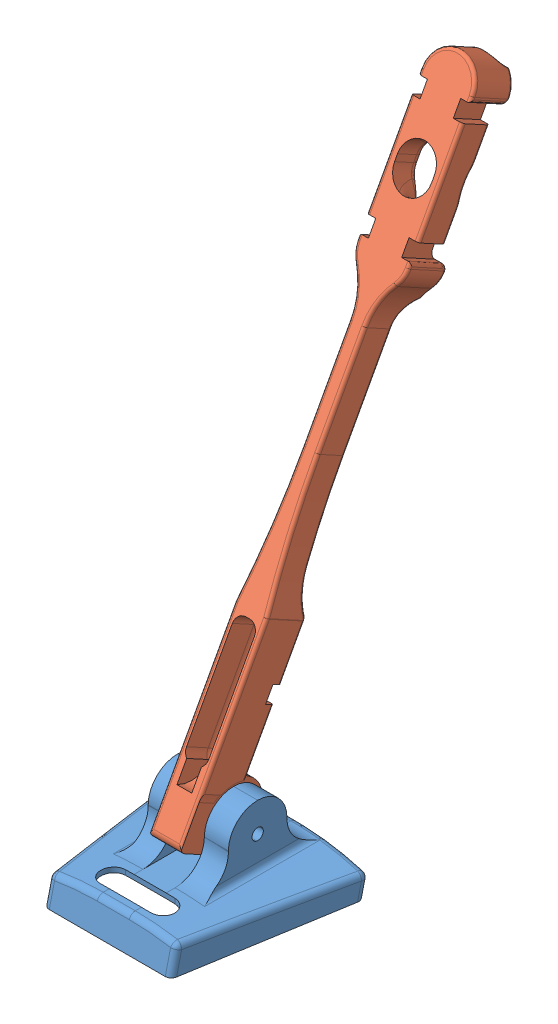
SolidWorks assembly Assem1, configuration Default. Lengths in mm.
Overall size (29.13 103.19 67.79).
2 component instances, 2 part files, 3 mates.
Components (placement in the parent):
- ant mount2-1: ant mount2 [Default] x (1 0 0) z (0 0.23129 0.972885) size (29.13 18.24 26.5)
- ant mount1-1: ant mount1 [Default] at (0 83.6021 -43.0844) x (1 0 0) z (0 0.478551 0.878059) size (8.4 100 12.28)
Mates (geometry in assembly coordinates):
- Width1: width anti-aligned: plane of ant mount2-1 through (-2.6 3.0626 -9.75) normal (1 0 0); plane of ant mount1-1 through (2.6 3.0626 -9.75) normal (-1 0 0); plane of ant mount2-1 through (-2.5 8.6925 -2.9112) normal (-1 0 0); plane of ant mount1-1 through (2.5 8.6925 -2.9112) normal (1 0 0)
- Concentric1: concentric anti-aligned: cylinder of ant mount1-1 through (9.5 12.679 -5) axis (-1 0 0) radius 0.925; cylinder of ant mount2-1 through (-14.5659 12.679 -5) axis (1 0 0) radius 0.925
- Parallel3: parallel aligned: plane of ant mount2-1 through (-10.25 14.0582 10.2772) normal (0 0.23129 0.972885); plane of ant mount1-1
